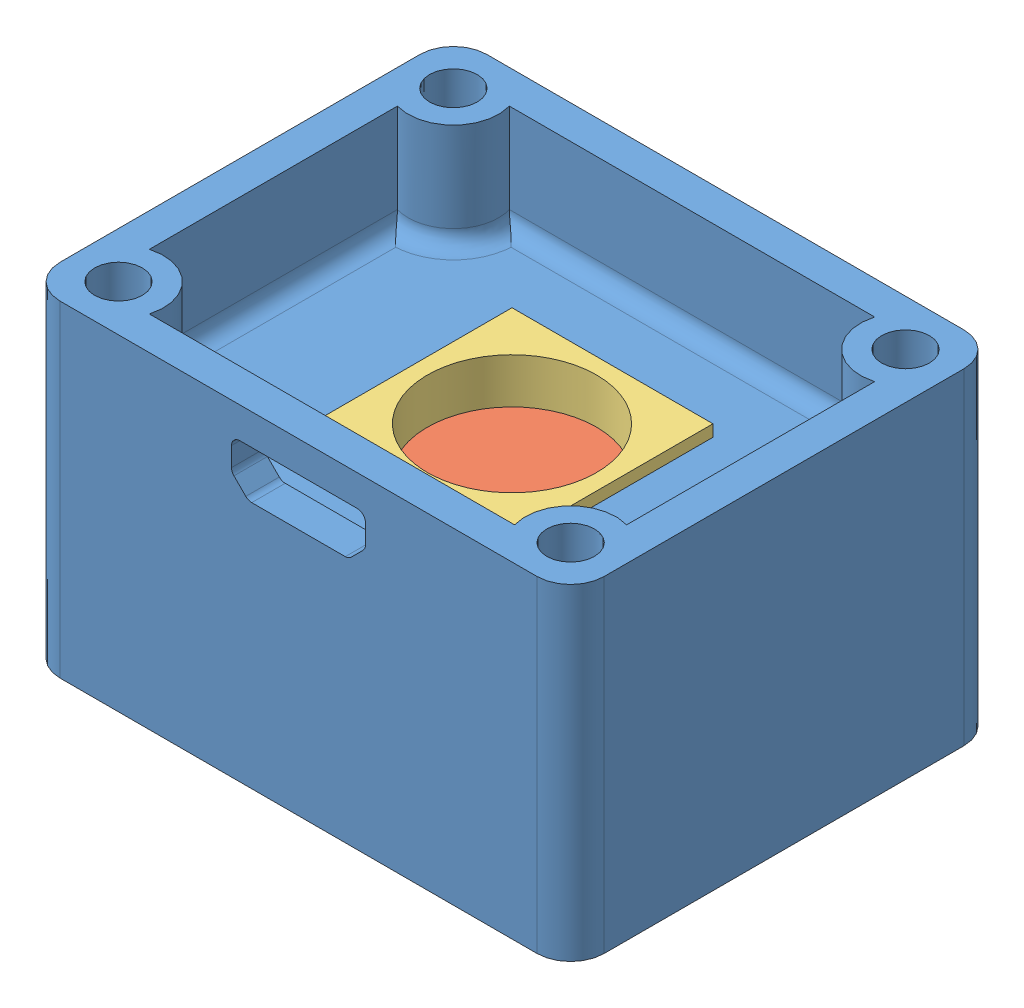
SolidWorks assembly Diffusion_Module-160-2, configuration Default. Lengths in mm.
Overall size (102 21.68 27.5).
4 component instances, 4 part files, 5 mates.
Components (placement in the parent):
- sensor_shell-160-2-1: sensor_shell-160-2 [Default] at origin size (102 21.68 27.5)
- acrylic_board-160-2-1: acrylic_board-160-2 [Default] at (0 9.2 0) size (14 2 14)
- black_ring-2: black_ring [默认] at (0 13.9 0) x (-1 0 0) z (0 0 1) size (12 2.7 12)
- diffusion^Diffusion_Module-160-2-1: diffusion^Diffusion_Module-160-2 [默认] at (0 22.5 0) x (-1 0 0) z (0 0 1) size (96 12.37 21.5) (virtual)
Mates (geometry in assembly coordinates):
- 宽度2: width aligned: plane of acrylic_board-160-2-1 through (-7 11.2 -7) normal (-1 0 0); plane of sensor_shell-160-2-1 through (7 11.2 -7) normal (1 0 0); plane of acrylic_board-160-2-1 through (-50 13.2 -12.75) normal (-1 0 0); plane of sensor_shell-160-2-1 through (50 13.2 -12.75) normal (1 0 0)
- 重合16: coincident anti-aligned: plane of sensor_shell-160-2-1 through (0 11.2 0) normal (0 -1 0); plane of acrylic_board-160-2-1 through (0 11.2 0) normal (0 1 0)
- 重合19: coincident anti-aligned: plane of acrylic_board-160-2-1 through (0 11.2 0) normal (0 1 0); plane of black_ring-2 through (0 11.2 0) normal (0 -1 0)
- 宽度5: width aligned: plane of black_ring-2 through (6 11.2 6) normal (0 0 1); plane of black_ring-2 through (6 11.2 -6) normal (0 0 -1); plane of sensor_shell-160-2-1 through (-6 11.2 -6) normal (0 0 1); plane of sensor_shell-160-2-1 through (-6 11.2 6) normal (0 0 -1)
- 宽度6: width anti-aligned: plane of black_ring-2 through (6 11.2 -6) normal (1 0 0); plane of black_ring-2 through (-6 11.2 -6) normal (-1 0 0); plane of sensor_shell-160-2-1 through (6 11.2 -6) normal (-1 0 0); plane of sensor_shell-160-2-1 through (-6 11.2 -6) normal (1 0 0)
